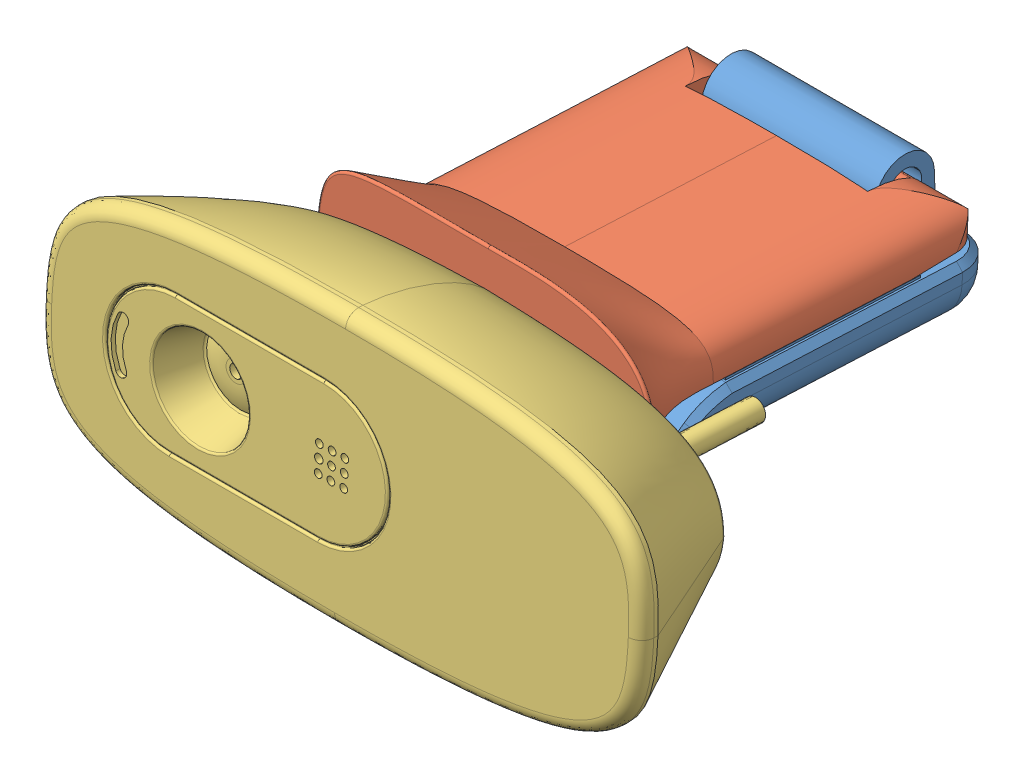
SolidWorks assembly c270, configuration Default. Lengths in mm.
Overall size (78.48 40.09 68.86).
3 component instances, 3 part files, 7 mates.
Components (placement in the parent):
- clip-2-1: clip-2 [Default] at (12.7536 -10.2877 49.9503) x (1 0 0) z (0 0.045214 0.998977) size (36 14.88 39.47)
- clip-1-1: clip-1 [Default] at (13.5036 -4.9626 73.6088) x (1 0 0) z (0 -0.045214 -0.998977) size (43.19 23.62 48.27)
- c270-corps-1: c270-corps [Default] at (18.796 -4.1051 93.9408) x (1 0 0) z (0 0.045214 0.998977) size (78.48 38.83 28.67)
Mates (geometry in assembly coordinates):
- Concentric1: concentric: cylinder of Logitech c270c-1 through (-5.2468 -4.2737 33.5366) axis (1 0 0) radius 2; cylinder of Logitech c270b-1 through (-1.2278 -4.2737 33.5366) axis (1 0 0) radius 1.1425
- Concentric2: concentric aligned: cylinder of Logitech c270b-1 through (35.1918 -4.8303 76.5308) axis (-1 0 0) radius 2; cylinder of Logitech c270-1 through (58.0352 -4.8303 76.5308) axis (-1 0 0) radius 2
- Distance1: distance = 0.25 mm anti-aligned: plane of Logitech c270-1 through (15.796 -8.5284 73.62) normal (1 0 0); plane of Logitech c270b-1 through (16.046 -1.1949 79.4444) normal (-1 0 0)
- Parallel1: parallel anti-aligned: plane of Logitech c270c-1; plane of Logitech c270b-1
- Distance2: distance = 0.5 mm: plane of Logitech c270c-1 through (23.0036 -0.3253 43.3633) normal (1 0 0); plane of Logitech c270b-1 through (23.5036 6.8203 73.0755) normal (-1 0 0)
- Parallèle1: parallel anti-aligned: plane of clip-1-1 through (-3.753 4.1256 73.1974) normal (0 0.045214 0.998977); plane of c270-corps-1 through (39.6416 3.5007 78.5812) normal (0 -0.045214 -0.998977)
- Parallèle2: parallel anti-aligned: plane of clip-2-1 through (12.7536 -6.042 49.7582) normal (0 0.998977 -0.045214); plane of clip-1-1 through (13.5036 -4.7128 73.5975) normal (0 -0.998977 0.045214)
